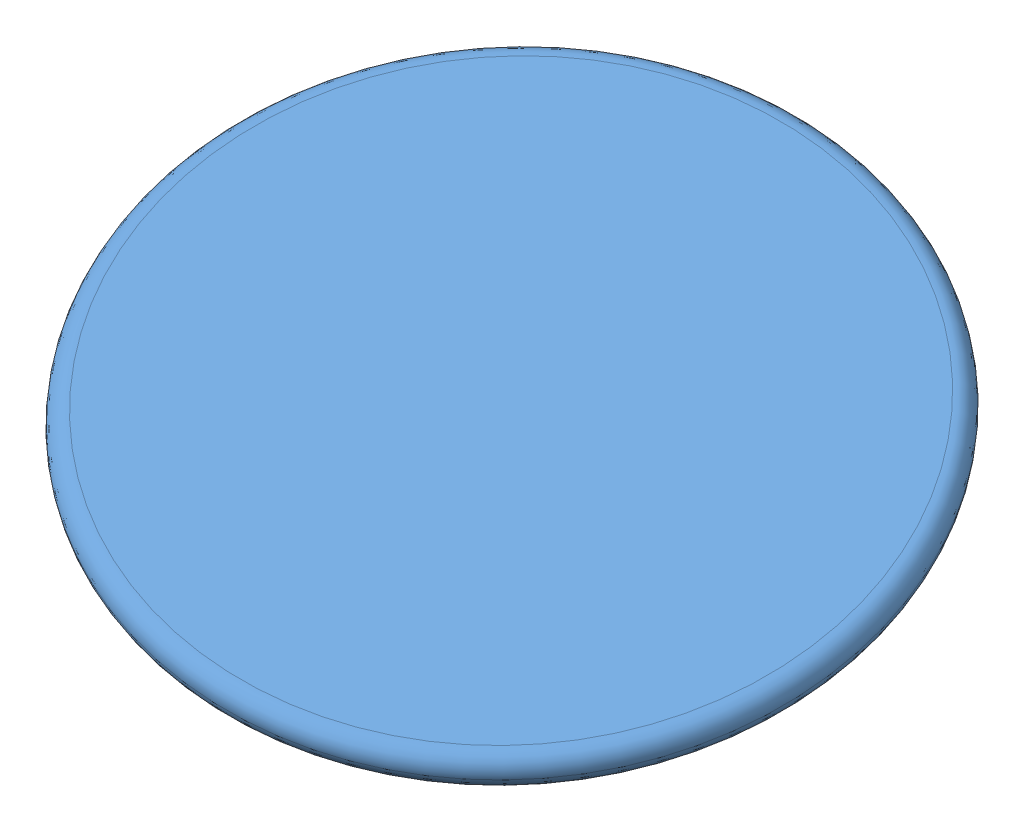
SolidWorks assembly righttURNwHEEL_1, configuration Default. Lengths in mm.
Overall size (787.04 358.81 796.32).
2 component instances, 2 part files, 0 mates.
Components (placement in the parent):
- pizza wheel_1-1: pizza wheel_1 [Default] at (-55.5421 176.9459 -250.9325) x (0.849801 -0.028004 -0.526359) z (-0.168606 -0.960565 -0.221106) size (558.8 558.8 196.32)
- steeringBracket_1-1: steeringBracket_1 [Default] at (-162.3551 92.8188 -446.3378) x (-0.849801 0.028004 0.526359) z (-0.49941 0.276643 -0.82101) size (93.42 20.57 203.2)
